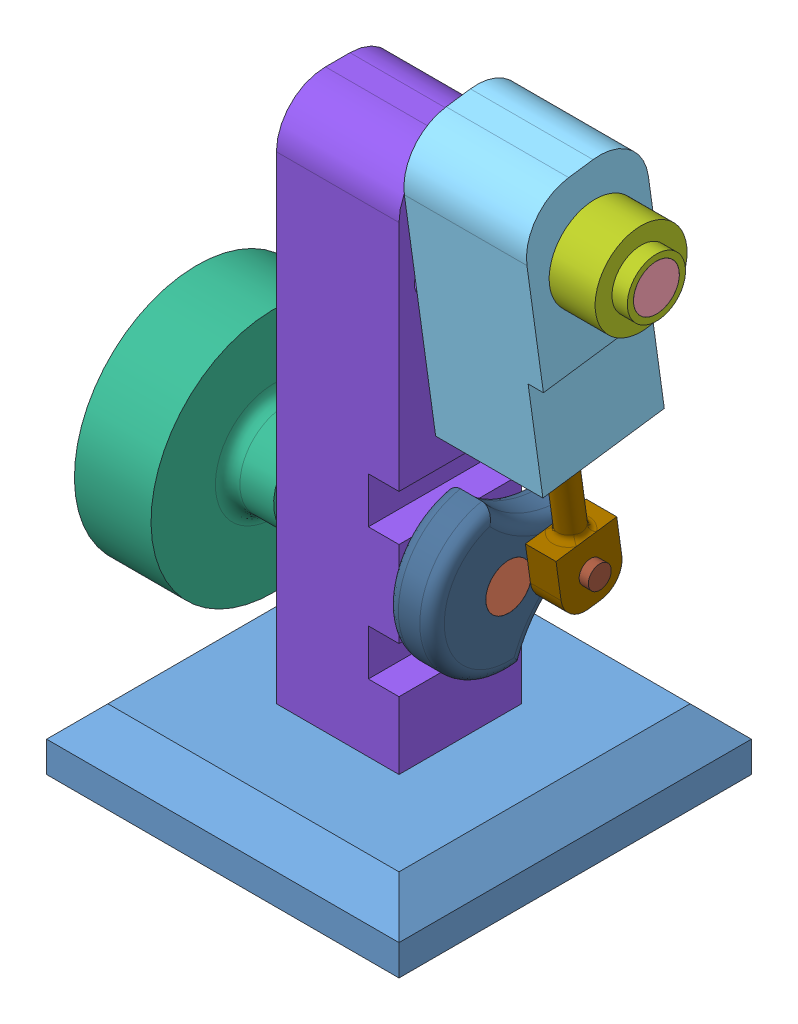
SolidWorks assembly ENGINE, configuration Default. Lengths in mm.
Overall size (3.77 5.18 8.54).
11 component instances, 11 part files, 24 mates.
Components (placement in the parent):
- BASE-1: BASE [Default] at (1.0968 1.1042 2.2936) size (2.88 0.5 2.88)
- BIG BAR-1: BIG BAR [Default] at (1.9918 2.8792 2.2936) x (0 0.448077 0.893995) z (0 -0.893995 0.448077) size (0.38 2.56 0.38)
- Bolt-1: Bolt [Default] at (1.0968 1.2292 2.2936) size (0.38 0.75 0.38)
- Connecting Bolt-1: Connecting Bolt [Default] at (3.1968 5.5942 2.2936) x (0 0.61595 0.787785) z (0 -0.787785 0.61595) size (0.38 2.25 0.38)
- Cylinder-1: Cylinder [Default] at (2.1043 3.9848 2.0694) x (1 0 0) z (0 -0.13793 0.990442) size (1 2.25 1)
- Fly Wheel-1: Fly Wheel [Default] at (0.0738 2.8792 2.2936) x (0 0.448077 0.893995) z (0 -0.893995 0.448077) size (2 1 2)
- HOLDER-1: HOLDER [Default] at (2.6968 5.5942 2.2936) x (0 -0.652541 0.757753) z (0 0.757753 0.652541) size (0.75 0.5 0.75)
- Main Body Part-1: Main Body Part [Default] at (1.0968 1.6042 2.2936) x (0 0 -1) z (1 0 0) size (7.6 4.3 1)
- Piston-1: Piston [Default] at (2.1668 4.5203 2.144) x (1 0 0) z (0 0.13793 -0.990442) size (0.5 1.83 0.5)
- Shaft Wheel-1: Shaft Wheel [Default] at (1.9918 2.8792 2.2936) x (0 0.981796 0.189941) z (0 -0.189941 0.981796) size (1.26 0.39 1.22)
- Small Bar-1: Small Bar [Default] at (1.6168 2.9505 1.9254) x (0 -0.942983 -0.332841) z (0 -0.332841 0.942983) size (0.19 0.75 0.19)
Mates (geometry in assembly coordinates):
- Concentric25: concentric anti-aligned: cylinder of Piston-1 through (2.0418 2.9505 1.9254) axis (1 0 0) radius 0.0935; cylinder of Small Bar-1 through (2.3668 2.9505 1.9254) axis (-1 0 0) radius 0.0935
- Concentric30: concentric anti-aligned: cylinder of BASE-1 through (1.0968 1.4792 2.2936) axis (0 1 0) radius 0.125; cylinder of Bolt-1 through (1.0968 1.9792 2.2936) axis (0 -1 0) radius 0.125
- Coincident1: coincident anti-aligned: plane of BASE-1 through (1.0968 1.4792 2.2936) normal (0 -1 0); plane of Bolt-1 through (1.0968 1.4792 2.2936) normal (0 1 0)
- Concentric31: concentric aligned: cylinder of Bolt-1 through (1.0968 1.9792 2.2936) axis (0 -1 0) radius 0.125; cylinder of Main Body Part-1 through (1.0968 2.3042 2.2936) axis (0 -1 0) radius 0.1
- Coincident2: coincident anti-aligned: plane of BASE-1 through (1.0968 1.6042 2.2936) normal (0 1 0); plane of Main Body Part-1 through (1.0968 1.6042 2.2936) normal (0 -1 0)
- Parallel26: parallel: line of BASE-1 through (2.2843 1.6042 3.4811) axis (0 0 -1); plane of Main Body Part-1 through (1.5968 5.9042 2.7936) normal (1 0 0)
- Concentric32: concentric aligned: cylinder of BIG BAR-1 through (-0.5712 2.8792 2.2936) axis (1 0 0) radius 0.1875; cylinder of Fly Wheel-1 through (-0.4262 2.8792 2.2936) axis (1 0 0) radius 0.1875
- Parallel27: parallel anti-aligned: line of BIG BAR-1 through (-0.5712 2.7587 2.4099) axis (0 0.893995 -0.448077); line of Fly Wheel-1 through (-0.5512 3.0952 2.2413) axis (0 -0.893995 0.448077)
- Coincident5: coincident anti-aligned: circle of BIG BAR-1; plane of Fly Wheel-1 through (-0.5512 2.8792 2.2936) normal (-1 0 0)
- Concentric34: concentric aligned: cylinder of BIG BAR-1 through (-0.5712 2.8792 2.2936) axis (1 0 0) radius 0.1875; cylinder of Main Body Part-1 through (0.5968 2.8792 2.2936) axis (1 0 0) radius 0.1875
- Concentric35: concentric anti-aligned: cylinder of Main Body Part-1 through (0.5968 2.8792 2.2936) axis (1 0 0) radius 0.1875; circle of Shaft Wheel-1
- Coincident7: coincident aligned: plane of BIG BAR-1 through (1.9918 2.8792 2.2936) normal (1 0 0); plane of Shaft Wheel-1 through (1.9918 2.0166 1.3621) normal (1 0 0)
- Concentric36: concentric anti-aligned: cylinder of Shaft Wheel-1 through (1.8048 2.9505 1.9254) axis (1 0 0) radius 0.0935; cylinder of Small Bar-1 through (2.3668 2.9505 1.9254) axis (-1 0 0) radius 0.0935
- Concentric37: concentric anti-aligned: cylinder of Piston-1 through (2.0418 2.9505 1.9254) axis (1 0 0) radius 0.0935; cylinder of Small Bar-1 through (2.3668 2.9505 1.9254) axis (-1 0 0) radius 0.0935
- Coincident9: coincident aligned: plane of Shaft Wheel-1 through (1.6168 2.0166 1.3621) normal (-1 0 0); plane of Small Bar-1 through (1.6168 2.9505 1.9254) normal (-1 0 0)
- Distance2: distance = 0.05 mm anti-aligned: plane of Piston-1 through (2.0418 2.6684 2.1385) normal (-1 0 0); plane of Shaft Wheel-1 through (1.9918 2.0166 1.3621) normal (1 0 0)
- Concentric38: concentric anti-aligned: circle of Connecting Bolt-1; circle of Main Body Part-1
- Coincident11: coincident anti-aligned: plane of Connecting Bolt-1 through (0.9468 5.5942 2.2936) normal (-1 0 0); plane of Main Body Part-1 through (0.9468 5.5942 2.2936) normal (1 0 0)
- Concentric39: concentric aligned: cylinder of Connecting Bolt-1 through (0.9468 5.5942 2.2936) axis (1 0 0) radius 0.1875; circle of HOLDER-1
- Coincident12: coincident aligned: plane of Connecting Bolt-1 through (3.1968 5.5942 2.2936) normal (1 0 0); circle of HOLDER-1
- Concentric40: concentric aligned: cylinder of Connecting Bolt-1 through (0.9468 5.5942 2.2936) axis (1 0 0) radius 0.1875; cylinder of Cylinder-1 through (1.6668 5.5942 2.2936) axis (1 0 0) radius 0.1875
- Distance3: distance = 0.07 mm anti-aligned: plane of Cylinder-1 through (1.6668 4.9204 1.6949) normal (-1 0 0); plane of Main Body Part-1 through (1.5968 5.9042 2.7936) normal (1 0 0)
- Concentric41: concentric anti-aligned: cylinder of Cylinder-1 through (2.1668 5.1614 2.2333) axis (0 -0.990442 -0.13793) radius 0.25; cylinder of Piston-1 through (2.1668 4.0895 2.084) axis (0 0.990442 0.13793) radius 0.25
- Lock1: lock: unknown of BIG BAR-1; unknown of Shaft Wheel-1
